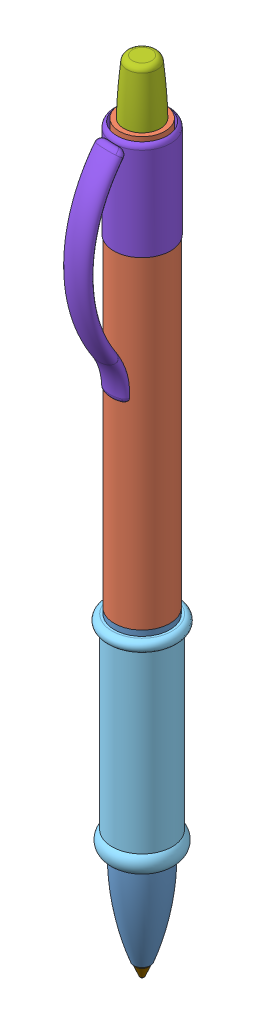
SolidWorks assembly PROJECT PEN ASSY, configuration Default. Lengths in mm.
Overall size (13.71 145.13 21.54).
10 component instances, 10 part files, 14 mates.
Components (placement in the parent):
- Pen part 1-1: Pen part 1 [Default] at origin size (10.08 67.85 10.08)
- Pen part 2-1: Pen part 2 [Default] at (0 55.61 0) size (10.11 77 10.11)
- Pen part 3-1: Pen part 3 [Default] at (0 111.7093 0) x (0.758031 0 -0.652219) z (0.652219 0 0.758031) size (7.83 15.04 7.83)
- Pen part 4-1: Pen part 4 [Default] at (0 10.6 0) x (0.988355 0 -0.152163) z (0.152163 0 0.988355) size (6.64 20.06 6.64)
- Pen part 5-1: Pen part 5 [Default] at (0 17.01 0) x (0.997899 0 0.064792) z (-0.064792 0 0.997899) size (12.9 37.6 12.9)
- Pen part 6-1: Pen part 6 [Default] at (0 5.6475 0) x (0.794583 0 -0.607156) z (0.607156 0 0.794583) size (6 105 6)
- Pen part 7-1: Pen part 7 [Default] at (0 120.754 0) x (0.208933 0 -0.97793) z (0.97793 0 0.208933) size (7.52 21.75 7.52)
- Pen part 8-2: Pen part 8 [Default] at (0 114.28 0) x (0.999142 0 0.041404) z (-0.041404 0 0.999142) size (10.32 41.18 19.65)
- Pen part 9-1: Pen part 9 [Default] at (0 -3.3525 0) x (0.917353 0 -0.398075) z (0.398075 0 0.917353) size (2.43 8 2.43)
- Pen part 10-1: Pen part 10 [Default] at (-0.0007 -2.6219 0.0201) size (0.68 0.72 0.68)
Mates (geometry in assembly coordinates):
- Concentric1: concentric aligned: circle of Pen part 1-1; circle of Pen part 2-1
- Coincident1: coincident anti-aligned: plane of Pen part 1-1 through (-4.04 55.61 0) normal (0 1 0); plane of Pen part 2-1 through (-4.055 55.61 0) normal (0 -1 0)
- Concentric2: concentric aligned: circle of Pen part 2-1; circle of Pen part 3-1
- Coincident2: coincident anti-aligned: plane of Pen part 1-1 through (-5.04 54.61 0) normal (0 -1 0); plane of Pen part 5-1 through (-4.1014 54.61 -0.2663) normal (0 1 0)
- Concentric3: concentric aligned: circle of Pen part 1-1; circle of Pen part 5-1
- Concentric4: concentric anti-aligned: circle of Pen part 1-1; circle of Pen part 4-1
- Concentric5: concentric aligned: circle of Pen part 1-1; circle of Pen part 6-1
- Concentric6: concentric anti-aligned: cylinder of Pen part 3-1; cylinder of Pen part 6-1 through (0 5.6475 0) axis (0 -1 0) radius 2.25
- Concentric7: concentric anti-aligned: circle of Pen part 2-1; circle of Pen part 7-1
- Coincident5: coincident aligned: plane of Pen part 1-1 through (-2.62 10.6 0) normal (0 1 0); circle of Pen part 4-1
- Concentric8: concentric aligned: circle of Pen part 2-1; circle of Pen part 8-2
- Coincident6: coincident anti-aligned: plane of Pen part 2-1 through (-5.055 114.28 0) normal (0 1 0); plane of Pen part 8-2 through (0 114.28 0) normal (0 -1 0)
- Concentric9: concentric aligned: circle of Pen part 6-1; circle of Pen part 9-1
- Coincident7: coincident anti-aligned: plane of Pen part 6-1 through (0.9441 5.6475 1.2356) normal (0 -1 0); plane of Pen part 9-1 through (-1.1146 5.6475 0.4837) normal (0 1 0)
